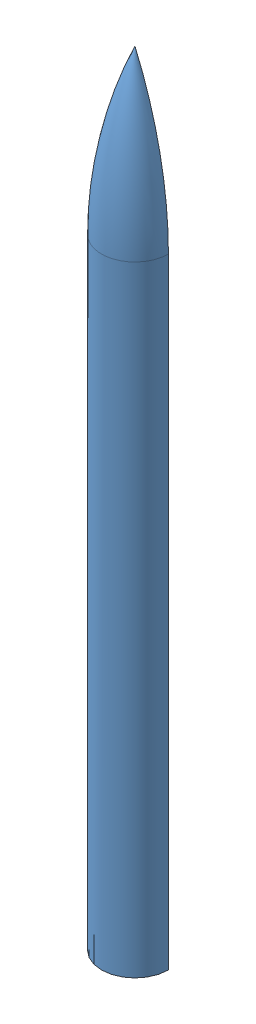
SolidWorks assembly LV4_Assembly, configuration Default. Lengths in mm.
Overall size (274.32 3209.54 137.16).
7 component instances, 7 part files, 21 mates.
Components (placement in the parent):
- LV4_Airframe-1: LV4_Airframe [Default] at (-137.16 0 0) size (274.32 3209.54 137.16)
- LV4_Ox-1: LV4_Ox [Default] at (-137.16 254 0) size (267.97 591.1 133.98)
- LV4_Fuel-1: LV4_Fuel [Default] at (-137.16 254 0) size (267.97 608.9 133.98)
- LV4_FeedSystem-1: LV4_FeedSystem [Default] at (-137.16 0 0) size (267.97 254 133.98)
- LV4_Recovery-1: LV4_Recovery [Default] at (-137.16 2387.6 0) size (267.97 152.4 133.98)
- LV4_Control-1: LV4_Control [Default] at (-137.16 1454 0) size (267.97 304.8 133.98)
- LV4_Computer-1: LV4_Computer [Default] at (-137.16 1758.8 0) size (267.97 628.8 133.98)
Mates (geometry in assembly coordinates):
- Concentric1: concentric aligned: cylinder of LV4_Airframe-1 through (-137.16 0 0) axis (0 -1 0) radius 133.985; cylinder of LV4_Fuel-1 through (-137.16 254 0) axis (0 -1 0) radius 133.985
- Concentric2: concentric aligned: cylinder of LV4_Airframe-1 through (-137.16 0 0) axis (0 -1 0) radius 133.985; cylinder of LV4_Ox-1 through (-137.16 254 0) axis (0 -1 0) radius 133.985
- Coincident3: coincident aligned: plane of LV4_Airframe-1 through (-137.16 0 0) normal (0 0 1); plane of assembly through (0 0 0) normal (0 0 1)
- Tangent3: tangent anti-aligned: sphere of LV4_Ox-1; sphere of LV4_Fuel-1
- Coincident4: coincident aligned: plane of LV4_Airframe-1 through (-1702.7633 2540 0) normal (0 0 -1); plane of LV4_Ox-1 through (-137.16 254 0) normal (0 0 -1)
- Coincident5: coincident aligned: plane of LV4_Ox-1 through (-137.16 254 0) normal (0 0 -1); plane of LV4_Fuel-1 through (-137.16 254 0) normal (0 0 -1)
- Coincident6: coincident anti-aligned: plane of LV4_Airframe-1 through (-1702.7633 2540 0) normal (0 0 -1); plane of assembly through (0 0 0) normal (0 0 1)
- Coincident7: coincident anti-aligned: circle of LV4_Airframe-1; plane of assembly through (0 0 0) normal (0 1 0)
- Coincident8: coincident: point of ?
- Coincident9: coincident aligned: plane of LV4_Airframe-1 through (0 0 0) normal (0 -1 0); plane of LV4_FeedSystem-1 through (-137.16 0 0) normal (0 -1 0)
- Coincident10: coincident aligned: plane of LV4_Airframe-1 through (-1702.7633 2540 0) normal (0 0 -1); plane of LV4_FeedSystem-1 through (-137.16 0 0) normal (0 0 -1)
- Concentric3: concentric aligned: cylinder of LV4_Airframe-1 through (-137.16 0 0) axis (0 -1 0) radius 133.985; cylinder of LV4_FeedSystem-1 through (-137.16 0 0) axis (0 -1 0) radius 133.985
- Coincident11: coincident: moEndPointRef_w of LV4_Fuel-1; plane of LV4_FeedSystem-1 through (-137.16 254 0) normal (0 1 0)
- Coincident12: coincident aligned: plane of LV4_FeedSystem-1 through (-137.16 0 0) normal (0 0 -1); plane of LV4_Recovery-1 through (-137.16 2387.6 0) normal (0 0 -1)
- Concentric4: concentric aligned: cylinder of LV4_Airframe-1 through (-137.16 0 0) axis (0 -1 0) radius 133.985; cylinder of LV4_Recovery-1 through (-137.16 2387.6 0) axis (0 -1 0) radius 133.985
- Coincident13: coincident anti-aligned: circle of LV4_Airframe-1; plane of LV4_Recovery-1 through (-137.16 2540 0) normal (0 1 0)
- Coincident14: coincident aligned: plane of LV4_Recovery-1 through (-137.16 2387.6 0) normal (0 0 -1); plane of LV4_Control-1 through (-137.16 1893.5584 0) normal (0 0 -1)
- Concentric5: concentric aligned: cylinder of LV4_Airframe-1 through (-137.16 0 0) axis (0 -1 0) radius 133.985; cylinder of LV4_Control-1 through (-137.16 1893.5584 0) axis (0 -1 0) radius 133.985
- Coincident16: coincident: moEndPointRef_w of LV4_Ox-1; plane of LV4_Control-1 through (-137.16 1454 0) normal (0 -1 0)
- Coincident17: coincident anti-aligned: plane of LV4_Recovery-1 through (-137.16 2387.6 0) normal (0 -1 0); plane of LV4_Computer-1 through (-137.16 2387.6 0) normal (0 1 0)
- Concentric6: concentric aligned: cylinder of LV4_Airframe-1 through (-137.16 0 0) axis (0 -1 0) radius 133.985; cylinder of LV4_Computer-1 through (-137.16 1758.8 0) axis (0 -1 0) radius 133.985
